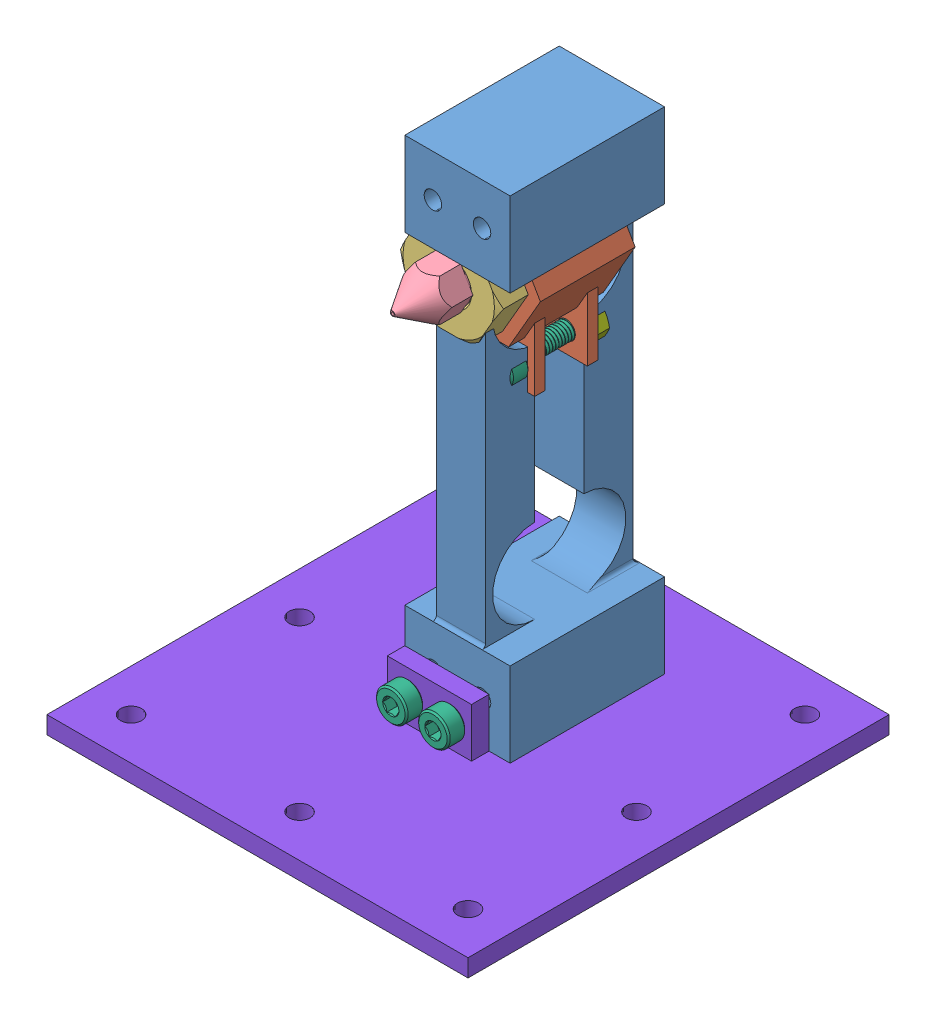
SolidWorks assembly Load Cell Assembly, configuration Default. Lengths in mm.
Overall size (60 72.5 60).
15 component instances, 8 part files, 33 mates.
Components (placement in the parent):
- E5_Load Cell-1: E5_Load Cell [Default] at (-1.4723 11.6667 38.7166) x (0 1 0) z (-1 0 0) size (70 22 15)
- M24_Nozzle Mount-1: M24_Nozzle Mount [Default] at (4.5277 66.5167 22.4666) size (18.13 22.2 13.5)
- Custom Nozzle Assembly-1: Custom Nozzle Assembly [Default] at (4.5277 66.5167 38.4666) x (0.866025 0.5 0) z (0 0 1) size (12.7 14.66 32.57)
  - M27_93020A775_LOW-STRENGTH STL HEX CPLG NUT-1: M27_93020A775_LOW-STRENGTH STL HEX CPLG NUT [93020A775] at origin size (12.7 14.66 16)
  - M20_Creality Brass Nozzle-1: M20_Creality Brass Nozzle [Default] at (0 0 8) size (6 7.32 13)
  - M21_5058K956_ALUMINUM LOW-PRESSURE BARBED TUBE FITTING-1: M21_5058K956_ALUMINUM LOW-PRESSURE BARBED TUBE FITTING [5058K956] at (0 0 -17.0319) x (0 0 -1) z (1 0 0) size (15.08 9.17 7.94)
- M25_91292A836_18-8 Stainless Steel Socket Head Screw-1: M25_91292A836_18-8 Stainless Steel Socket Head Screw [91292A836] at (1.5277 55.1667 17.2166) x (-0.866025 -0.5 0) z (0 0 -1) size (4.5 4.5 17.7)
- M25_91292A836_18-8 Stainless Steel Socket Head Screw-2: M25_91292A836_18-8 Stainless Steel Socket Head Screw [91292A836] at (7.5277 55.1667 17.2166) x (-0.866025 -0.5 0) z (0 0 -1) size (4.5 4.5 17.7)
- M26_91828A113_18-8 Stainless Steel Hex Nut-1: M26_91828A113_18-8 Stainless Steel Hex Nut [91828A113] at (1.5277 55.1667 22.2166) x (0.866025 -0.5 0) z (0 0 1) size (5 5.77 2.25)
- M26_91828A113_18-8 Stainless Steel Hex Nut-3: M26_91828A113_18-8 Stainless Steel Hex Nut [91828A113] at (7.5277 55.1667 22.2166) x (0.866025 0.5 0) z (0 0 1) size (5 5.77 2.25)
- M23_Load Cell Plate-1: M23_Load Cell Plate [Default] at (4.5277 9.1667 35.7166) x (0 0 1) z (-1 0 0) size (60 9.5 60)
- M25_91292A836_18-8 Stainless Steel Socket Head Screw-3: M25_91292A836_18-8 Stainless Steel Socket Head Screw [91292A836] at (1.5277 15.1667 26.2166) x (-0.866025 -0.5 0) z (0 0 -1) size (4.5 4.5 17.7)
- M25_91292A836_18-8 Stainless Steel Socket Head Screw-4: M25_91292A836_18-8 Stainless Steel Socket Head Screw [91292A836] at (7.5277 15.1667 26.2166) x (0 -1 0) z (0 0 -1) size (4.5 4.5 17.7)
- M26_91828A113_18-8 Stainless Steel Hex Nut-4: M26_91828A113_18-8 Stainless Steel Hex Nut [91828A113] at (7.5277 15.1667 29.2166) x (0 -1 0) z (0 0 1) size (5 5.77 2.25)
- M26_91828A113_18-8 Stainless Steel Hex Nut-5: M26_91828A113_18-8 Stainless Steel Hex Nut [91828A113] at (1.5277 15.1667 29.2166) x (0.866025 -0.5 0) z (0 0 1) size (5 5.77 2.25)
Mates (geometry in assembly coordinates):
- Concentric1: concentric: cylinder of Load Cell_New-1 through (9.5277 75.6667 16.7166) axis (0 0 -1) radius 1.25; cylinder of Nozzle Mount_New-1 through (7.5277 55.1667 20.9666) axis (0 0 1) radius 1.3
- Concentric2: concentric: cylinder of Load Cell_New-1 through (2.5277 75.6667 16.7166) axis (0 0 -1) radius 1.25; cylinder of Nozzle Mount_New-1 through (1.5277 55.1667 20.9666) axis (0 0 1) radius 1.3
- Width1: width aligned: plane of Nozzle Mount_New-1 through (-1.4723 52.1667 30.7166) normal (0 0 -1); plane of Load Cell_New-1 through (-1.4723 52.1667 24.7166) normal (0 0 1); plane of Nozzle Mount_New-1 through (-1.4723 11.6667 16.7166) normal (0 0 -1); plane of Load Cell_New-1 through (-1.4723 11.6667 38.7166) normal (0 0 1)
- Coincident1: coincident anti-aligned: plane of Nozzle Mount_New-1 through (8.1939 72.8667 34.4666) normal (0 -1 0); plane of Custom Nozzle Assembly-1/93020A775_LOW-STRENGTH STL HEX CPLG NUT-1 through (8.1939 72.8667 22.4666) normal (0 1 0)
- Coincident2: coincident anti-aligned: plane of Nozzle Mount_New-1 through (-2.8046 66.5167 34.4666) normal (0.866025 0.5 0); plane of Custom Nozzle Assembly-1/93020A775_LOW-STRENGTH STL HEX CPLG NUT-1 through (-2.8046 66.5167 22.4666) normal (-0.866025 -0.5 0)
- Coincident3: coincident anti-aligned: plane of Nozzle Mount_New-1 through (4.5277 66.5167 22.4666) normal (0 0 1); plane of Custom Nozzle Assembly-1/93020A775_LOW-STRENGTH STL HEX CPLG NUT-1 through (-6.7306 73.0167 22.4666) normal (0 0 -1)
- Coincident10: coincident anti-aligned: plane of Nozzle Mount_New-1 through (-1.4723 52.1667 32.2166) normal (0 0 1); plane of 91292A836_18-8 Stainless Steel Socket Head Screw-2 through (7.5277 55.1667 32.2166) normal (0 0 -1)
- Concentric7: concentric anti-aligned: cylinder of Nozzle Mount_New-1 through (7.5277 55.1667 20.9666) axis (0 0 1) radius 1.3; cylinder of 91292A836_18-8 Stainless Steel Socket Head Screw-2 through (7.5277 55.1667 34.7166) axis (0 0 -1) radius 2.25
- Coincident11: coincident anti-aligned: plane of Nozzle Mount_New-1 through (-1.4723 52.1667 32.2166) normal (0 0 1); plane of 91292A836_18-8 Stainless Steel Socket Head Screw-1 through (1.5277 55.1667 32.2166) normal (0 0 -1)
- Concentric8: concentric anti-aligned: cylinder of Nozzle Mount_New-1 through (1.5277 55.1667 20.9666) axis (0 0 1) radius 1.3; cylinder of 91292A836_18-8 Stainless Steel Socket Head Screw-1 through (1.5277 55.1667 34.7166) axis (0 0 -1) radius 2.25
- Parallel2: parallel aligned: plane of Nozzle Mount_New-1 through (4.5277 52.1667 22.4666) normal (0 -1 0); plane of 91292A836_18-8 Stainless Steel Socket Head Screw-1 through (2.1051 56.1667 33.2166) normal (0 -1 0)
- Parallel3: parallel aligned: plane of Nozzle Mount_New-1 through (4.5277 52.1667 22.4666) normal (0 -1 0); plane of 91292A836_18-8 Stainless Steel Socket Head Screw-2 through (8.1051 56.1667 33.2166) normal (0 -1 0)
- Concentric9: concentric aligned: circle of Nozzle Mount_New-1; circle of 91828A113_18-8 Stainless Steel Hex Nut-1
- Coincident14: coincident anti-aligned: plane of Nozzle Mount_New-1 through (-1.4723 52.1667 23.2166) normal (0 0 -1); plane of 91828A113_18-8 Stainless Steel Hex Nut-1 through (0.0843 57.6667 23.2166) normal (0 0 1)
- Parallel4: parallel anti-aligned: plane of Nozzle Mount_New-1 through (4.5277 52.1667 22.4666) normal (0 -1 0); plane of 91828A113_18-8 Stainless Steel Hex Nut-1 through (2.9711 57.6667 23.2166) normal (0 1 0)
- Concentric10: concentric aligned: circle of Nozzle Mount_New-1; circle of 91828A113_18-8 Stainless Steel Hex Nut-3
- Coincident18: coincident anti-aligned: plane of Nozzle Mount_New-1 through (-1.4723 52.1667 23.2166) normal (0 0 -1); plane of 91828A113_18-8 Stainless Steel Hex Nut-3 through (4.641 55.1667 23.2166) normal (0 0 1)
- Parallel7: parallel anti-aligned: plane of Nozzle Mount_New-1 through (4.5277 52.1667 22.4666) normal (0 -1 0); plane of 91828A113_18-8 Stainless Steel Hex Nut-3 through (8.9711 57.6667 23.2166) normal (0 1 0)
- Concentric11: concentric: cylinder of Load Cell_New-1 through (2.5277 17.6667 16.7166) axis (0 0 -1) radius 1.25; cylinder of Load Cell Plate-1 through (1.5277 15.1667 44.7522) axis (0 0 -1) radius 1.25
- Concentric12: concentric: cylinder of Load Cell_New-1 through (9.5277 17.6667 16.7166) axis (0 0 -1) radius 1.25; cylinder of Load Cell Plate-1 through (7.5277 15.1667 44.7522) axis (0 0 -1) radius 1.25
- Coincident19: coincident anti-aligned: plane of Load Cell_New-1 through (-1.4723 11.6667 38.7166) normal (0 0 1); plane of Load Cell Plate-1 through (-1.4723 18.6667 38.7166) normal (0 0 -1)
- Concentric13: concentric aligned: cylinder of Load Cell Plate-1 through (7.5277 15.1667 44.7522) axis (0 0 -1) radius 1.25; cylinder of 91292A836_18-8 Stainless Steel Socket Head Screw-4 through (7.5277 15.1667 43.7166) axis (0 0 -1) radius 2.25
- Concentric14: concentric aligned: cylinder of Load Cell Plate-1 through (1.5277 15.1667 44.7522) axis (0 0 -1) radius 1.25; cylinder of 91292A836_18-8 Stainless Steel Socket Head Screw-3 through (1.5277 15.1667 43.7166) axis (0 0 -1) radius 2.25
- Coincident20: coincident anti-aligned: plane of Load Cell Plate-1 through (-1.4723 18.6667 41.2166) normal (0 0 1); plane of 91292A836_18-8 Stainless Steel Socket Head Screw-4 through (7.5277 15.1667 41.2166) normal (0 0 -1)
- Coincident21: coincident anti-aligned: plane of Load Cell Plate-1 through (-1.4723 18.6667 41.2166) normal (0 0 1); plane of 91292A836_18-8 Stainless Steel Socket Head Screw-3 through (1.5277 15.1667 41.2166) normal (0 0 -1)
- Parallel8: parallel aligned: plane of Load Cell Plate-1 through (4.5277 11.6667 35.7166) normal (0 1 0); plane of 91292A836_18-8 Stainless Steel Socket Head Screw-3 through (0.9504 14.1667 42.2166) normal (0 1 0)
- Parallel9: parallel aligned: plane of Load Cell Plate-1 through (4.5277 11.6667 35.7166) normal (0 1 0); plane of 91292A836_18-8 Stainless Steel Socket Head Screw-4 through (6.9504 14.1667 42.2166) normal (0 1 0)
- Concentric15: concentric anti-aligned: circle of Load Cell Plate-1; circle of 91828A113_18-8 Stainless Steel Hex Nut-4
- Coincident24: coincident anti-aligned: plane of Load Cell Plate-1 through (-1.4723 18.6667 30.2166) normal (0 0 -1); plane of 91828A113_18-8 Stainless Steel Hex Nut-4 through (8.9711 17.6667 30.2166) normal (0 0 1)
- Parallel10: parallel aligned: plane of Load Cell Plate-1 through (4.5277 11.6667 35.7166) normal (0 1 0); plane of 91828A113_18-8 Stainless Steel Hex Nut-4 through (8.9711 17.6667 30.2166) normal (0 1 0)
- Concentric16: concentric aligned: circle of Load Cell Plate-1; circle of 91828A113_18-8 Stainless Steel Hex Nut-5
- Coincident26: coincident anti-aligned: plane of Load Cell Plate-1 through (-1.4723 18.6667 30.2166) normal (0 0 -1); plane of 91828A113_18-8 Stainless Steel Hex Nut-5 through (0.0843 17.6667 30.2166) normal (0 0 1)
- Parallel11: parallel aligned: plane of Load Cell Plate-1 through (4.5277 11.6667 35.7166) normal (0 1 0); plane of 91828A113_18-8 Stainless Steel Hex Nut-5 through (2.9711 17.6667 30.2166) normal (0 1 0)
